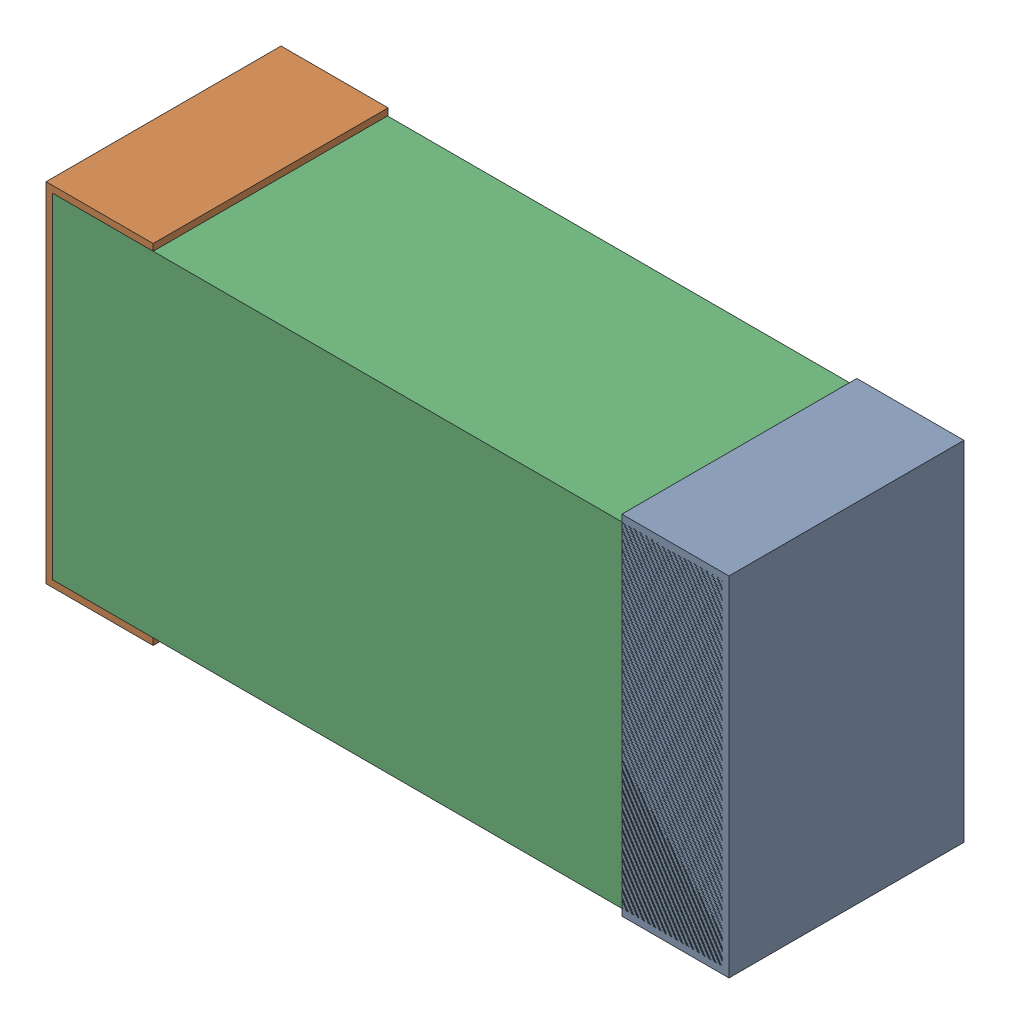
SolidWorks assembly R53, configuration Default. Lengths in mm.
Overall size (1.02 0.52 0.35).
6 component instances, 2 part files, 0 mates.
Components (placement in the parent):
- 870940480-1: 870940480 [Default] at (7.8976 25.146 -1.9516) size (0.16 0.52 0.35)
  - Extruded-1: Extruded [Default] at origin size (0.16 0.52 0.35)
- 870940480-2: 870940480 [Default] at (7.0376 25.146 -1.9516) size (0.16 0.52 0.35)
  - Extruded-1: Extruded [Default] at origin size (0.16 0.52 0.35)
- 870940640-1: 870940640 [Default] at (7.4676 25.146 -1.9506) size (1 0.5 0.35)
  - Extruded_2-1: Extruded_2 [Default] at origin size (1 0.5 0.35)
